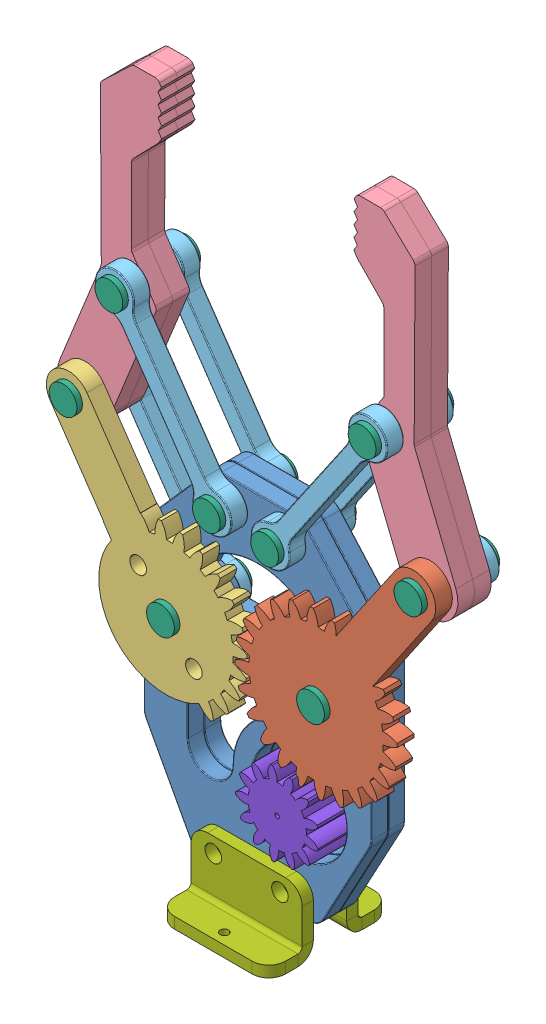
SolidWorks assembly Assem6, configuration Default. Lengths in mm.
Overall size (95 125.62 22).
25 component instances, 8 part files, 47 mates.
Components (placement in the parent):
- Part3-3-1: Part3-3 [Default] at origin size (41 62 3.03)
- part4-4-1: part4-4 [Default] at (13.5 37.5997 3) x (0 0 1) z (-0.565431 -0.824796 0) size (3 29.07 49.54)
- part5-5-1: part5-5 [Default] at (-13.5 37.5997 6) x (0 0 -1) z (0.668251 -0.743936 0) size (3 26.63 49.27)
- Part1-1-1: Part1-1 [Default] at (-31.0284 63.1684 0) x (0.375052 0.927004 0) z (0 0 1) size (60.3 20.75 3)
- Part2-2-1: Part2-2 [Default] at (-5.2398 58 4.5) x (-0.565723 0.824596 0) z (0 0 1) size (38 7 3)
- Part2-2-2: Part2-2 [Default] at (5.2398 58 4.5) x (0.565723 0.824596 0) z (0 0 1) size (38 7 3)
- Part1-1-2: Part1-1 [Default] at (31.0284 63.1684 3) x (-0.375052 0.927004 0) z (0 0 -1) size (60.3 20.75 3)
- Part3-3-2: Part3-3 [Default] at (0 0 -3) size (41 62 3.03)
- Part1-1-3: Part1-1 [Default] at (31.0284 63.1684 0) x (-0.375052 0.927004 0) z (0 0 -1) size (60.3 20.75 3)
- Part1-1-4: Part1-1 [Default] at (-31.0284 63.1684 -3) x (0.375052 0.927004 0) z (0 0 1) size (60.3 20.75 3)
- Part2-2-5: Part2-2 [Default] at (-5.2398 58 -4.5) x (-0.565723 0.824596 0) z (0 0 1) size (38 7 3)
- Part2-2-6: Part2-2 [Default] at (5.2398 58 -4.5) x (0.565723 0.824596 0) z (0 0 1) size (38 7 3)
- Part2-2-9: Part2-2 [Default] at (13.5 37.5997 -4.5) x (0.565431 0.824796 0) z (0 0 1) size (38 7 3)
- Part2-2-10: Part2-2 [Default] at (-13.5 37.5997 -4.5) x (-0.565431 0.824796 0) z (0 0 1) size (38 7 3)
- Part6-6-1: Part6-6 [Default] at (13.5 37.5997 7) x (1 0 0) z (0 1 0) size (5 14 5)
- Part7-7-1: Part7-7 [Default] at (0 -5.279 3) x (0 -1 0) z (-1 0 0) size (12 8 20)
- Part6-6-2: Part6-6 [Default] at (-13.5 37.5997 -7) x (-0.923728 -0.383049 0) z (-0.383049 0.923728 0) size (5 14 5)
- Part6-6-3: Part6-6 [Default] at (-31.0284 63.1684 -7) x (-0.923728 -0.383049 0) z (-0.383049 0.923728 0) size (5 14 5)
- Part6-6-4: Part6-6 [Default] at (-5.2398 58 -7) x (0.923728 0.383049 0) z (0.383049 -0.923728 0) size (5 14 5)
- Part6-6-5: Part6-6 [Default] at (-22.7772 83.5625 -7) x (0.923728 0.383049 0) z (0.383049 -0.923728 0) size (5 14 5)
- Part6-6-6: Part6-6 [Default] at (22.7772 83.5625 -7) x (0.923728 0.383049 0) z (0.383049 -0.923728 0) size (5 14 5)
- Part6-6-7: Part6-6 [Default] at (5.2398 58 -7) x (0.923728 0.383049 0) z (0.383049 -0.923728 0) size (5 14 5)
- Part6-6-8: Part6-6 [Default] at (31.0284 63.1684 -7) x (0.923728 0.383049 0) z (0.383049 -0.923728 0) size (5 14 5)
- Part7-7-3: Part7-7 [Default] at (0 -5.279 -3) x (0 -1 0) z (1 0 0) size (12 8 20)
- part8-8-1: part8-8 [Default] at (7.5 17.5997 7) x (0 0 -1) z (0.835413 -0.549623 0) size (13 17.5 17.5)
Mates (geometry in assembly coordinates):
- Concentric1: concentric aligned: cylinder of Part3-3-1 through (13.5 37.5997 3) axis (0 0 -1) radius 1.5; cylinder of part4-4-1 through (13.5 37.5997 53.0001) axis (0 0 -1) radius 1.5
- Coincident1: coincident anti-aligned: plane of Part3-3-1 through (0 0 3) normal (0 0 1); plane of part4-4-1 through (13.5 37.5997 3) normal (0 0 -1)
- Concentric2: concentric anti-aligned: cylinder of Part3-3-1 through (-13.5 37.5997 3) axis (0 0 -1) radius 1.5; cylinder of part5-5-1 through (-13.5 37.5997 -44.0001) axis (0 0 1) radius 1.5
- Coincident3: coincident anti-aligned: plane of Part3-3-1 through (0 0 3) normal (0 0 1); plane of part5-5-1 through (-13.5 37.5997 3) normal (0 0 -1)
- Concentric3: concentric aligned: cylinder of Part3-3-1 through (-5.2398 58 3) axis (0 0 -1) radius 1.5; cylinder of Part2-2-1 through (-5.2398 58 6) axis (0 0 -1) radius 1.5
- Coincident4: coincident anti-aligned: plane of Part3-3-1 through (0 0 3) normal (0 0 1); plane of Part2-2-1 through (-5.2398 58 3) normal (0 0 -1)
- Concentric4: concentric anti-aligned: cylinder of part5-5-1 through (-31.0284 63.1684 3) axis (0 0 1) radius 1.5; cylinder of Part1-1-1 through (-31.0284 63.1684 3) axis (0 0 -1) radius 1.5
- Concentric5: concentric aligned: cylinder of Part1-1-1 through (-22.7772 83.5625 3) axis (0 0 -1) radius 1.5; cylinder of Part2-2-1 through (-22.7772 83.5625 6) axis (0 0 -1) radius 1.5
- Concentric6: concentric anti-aligned: cylinder of part4-4-1 through (31.0284 63.1684 6) axis (0 0 -1) radius 1.5; cylinder of Part1-1-2 through (31.0284 63.1684 0) axis (0 0 1) radius 1.5
- Concentric7: concentric aligned: cylinder of Part3-3-1 through (5.2398 58 3) axis (0 0 -1) radius 1.5; cylinder of Part2-2-2 through (5.2398 58 6) axis (0 0 -1) radius 1.5
- Concentric8: concentric anti-aligned: cylinder of Part2-2-2 through (22.7772 83.5625 6) axis (0 0 -1) radius 1.5; cylinder of Part1-1-2 through (22.7772 83.5625 0) axis (0 0 1) radius 1.5
- Coincident8: coincident anti-aligned: plane of part4-4-1 through (13.5 37.5997 3) normal (0 0 -1); plane of Part1-1-2 through (31.0284 63.1684 3) normal (0 0 1)
- Coincident9: coincident anti-aligned: plane of part5-5-1 through (-13.5 37.5997 3) normal (0 0 -1); plane of Part1-1-1 through (-31.0284 63.1684 3) normal (0 0 1)
- Coincident10: coincident anti-aligned: plane of Part3-3-1 through (0 0 3) normal (0 0 1); plane of Part2-2-2 through (5.2398 58 3) normal (0 0 -1)
- Concentric11: concentric aligned: cylinder of Part3-3-2 through (13.5 37.5997 0) axis (0 0 -1) radius 1.5; cylinder of Part2-2-9 through (13.5 37.5997 -3) axis (0 0 -1) radius 1.5
- Concentric12: concentric anti-aligned: cylinder of Part1-1-3 through (31.0284 63.1684 -3) axis (0 0 1) radius 1.5; cylinder of Part2-2-9 through (31.0284 63.1684 -3) axis (0 0 -1) radius 1.5
- Coincident11: coincident anti-aligned: plane of Part3-3-2 through (0 0 -3) normal (0 0 -1); plane of Part2-2-9 through (13.5 37.5997 -3) normal (0 0 1)
- Concentric13: concentric aligned: cylinder of Part3-3-2 through (-13.5 37.5997 0) axis (0 0 -1) radius 1.5; cylinder of Part2-2-10 through (-13.5 37.5997 -3) axis (0 0 -1) radius 1.5
- Concentric14: concentric aligned: cylinder of Part1-1-4 through (-31.0284 63.1684 0) axis (0 0 -1) radius 1.5; cylinder of Part2-2-10 through (-31.0284 63.1684 -3) axis (0 0 -1) radius 1.5
- Coincident12: coincident anti-aligned: plane of Part3-3-2 through (0 0 -3) normal (0 0 -1); plane of Part2-2-10 through (-13.5 37.5997 -3) normal (0 0 1)
- Concentric15: concentric anti-aligned: cylinder of part4-4-1 through (13.5 37.5997 53.0001) axis (0 0 -1) radius 1.5; cylinder of Part6-6-1 through (13.5 37.5997 7) axis (0 0 1) radius 1.5
- Coincident15: coincident anti-aligned: plane of Part2-2-9 through (13.5 37.5997 -6) normal (0 0 -1); plane of Part6-6-1 through (11 37.5997 -6) normal (0 0 1)
- Coincident16: coincident anti-aligned: plane of Part3-3-1 through (0 0 3) normal (0 0 1); plane of Part7-7-1 through (-10 -5.279 3) normal (0 0 -1)
- Concentric16: concentric anti-aligned: cylinder of Part3-3-1 through (-6 4 3) axis (0 0 -1) radius 1.5; cylinder of Part7-7-1 through (-6 4 3) axis (0 0 1) radius 1.5
- Concentric17: concentric anti-aligned: cylinder of Part3-3-1 through (6 4 3) axis (0 0 -1) radius 1.5; cylinder of Part7-7-1 through (6 4 3) axis (0 0 1) radius 1.5
- Concentric18: concentric anti-aligned: cylinder of part5-5-1 through (-13.5 37.5997 -44.0001) axis (0 0 1) radius 1.5; cylinder of Part6-6-2 through (-13.5 37.5997 -7) axis (0 0 -1) radius 1.5
- Coincident17: coincident anti-aligned: plane of part5-5-1 through (-13.5 37.5997 6) normal (0 0 1); plane of Part6-6-2 through (-11.1907 38.5573 6) normal (0 0 -1)
- Concentric19: concentric anti-aligned: cylinder of part5-5-1 through (-31.0284 63.1684 3) axis (0 0 1) radius 1.5; cylinder of Part6-6-3 through (-31.0284 63.1684 -7) axis (0 0 -1) radius 1.5
- Coincident18: coincident anti-aligned: plane of part5-5-1 through (-13.5 37.5997 6) normal (0 0 1); plane of Part6-6-3 through (-28.719 64.126 6) normal (0 0 -1)
- Concentric20: concentric aligned: cylinder of Part2-2-1 through (-5.2398 58 6) axis (0 0 -1) radius 1.5; cylinder of Part6-6-4 through (-5.2398 58 -7) axis (0 0 -1) radius 1.5
- Coincident19: coincident anti-aligned: plane of Part2-2-1 through (-5.2398 58 6) normal (0 0 1); plane of Part6-6-4 through (-7.5491 57.0424 6) normal (0 0 -1)
- Concentric21: concentric aligned: cylinder of Part2-2-1 through (-22.7772 83.5625 6) axis (0 0 -1) radius 1.5; cylinder of Part6-6-5 through (-22.7772 83.5625 -7) axis (0 0 -1) radius 1.5
- Coincident20: coincident anti-aligned: plane of Part2-2-1 through (-5.2398 58 6) normal (0 0 1); plane of Part6-6-5 through (-25.0865 82.6048 6) normal (0 0 -1)
- Concentric22: concentric aligned: cylinder of Part2-2-2 through (22.7772 83.5625 6) axis (0 0 -1) radius 1.5; cylinder of Part6-6-6 through (22.7772 83.5625 -7) axis (0 0 -1) radius 1.5
- Coincident21: coincident anti-aligned: plane of Part2-2-2 through (5.2398 58 6) normal (0 0 1); plane of Part6-6-6 through (20.4679 82.6048 6) normal (0 0 -1)
- Concentric23: concentric aligned: cylinder of Part2-2-2 through (5.2398 58 6) axis (0 0 -1) radius 1.5; cylinder of Part6-6-7 through (5.2398 58 -7) axis (0 0 -1) radius 1.5
- Coincident22: coincident anti-aligned: plane of Part2-2-2 through (5.2398 58 6) normal (0 0 1); plane of Part6-6-7 through (2.9305 57.0424 6) normal (0 0 -1)
- Concentric24: concentric aligned: cylinder of part4-4-1 through (31.0284 63.1684 6) axis (0 0 -1) radius 1.5; cylinder of Part6-6-8 through (31.0284 63.1684 -7) axis (0 0 -1) radius 1.5
- Coincident23: coincident anti-aligned: plane of part4-4-1 through (13.5 37.5997 6) normal (0 0 1); plane of Part6-6-8 through (28.719 62.2108 6) normal (0 0 -1)
- Coincident25: coincident anti-aligned: plane of Part3-3-2 through (0 0 -3) normal (0 0 -1); plane of Part7-7-3 through (10 -5.279 -3) normal (0 0 1)
- Concentric27: concentric aligned: cylinder of Part3-3-2 through (6 4 0) axis (0 0 -1) radius 1.5; cylinder of Part7-7-3 through (6 4 -3) axis (0 0 -1) radius 1.5
- Concentric28: concentric aligned: cylinder of Part3-3-2 through (-6 4 0) axis (0 0 -1) radius 1.5; cylinder of Part7-7-3 through (-6 4 -3) axis (0 0 -1) radius 1.5
- Concentric29: concentric anti-aligned: cylinder of Part3-3-1 through (7.5 17.5997 3) axis (0 0 -1) radius 8.5; cylinder of part8-8-1 through (7.5 17.5997 -6) axis (0 0 1) radius 8.75
- Coincident26: coincident anti-aligned: plane of Part3-3-2 through (0 0 -3) normal (0 0 -1); plane of part8-8-1 through (7.5 17.5997 -3) normal (0 0 1)
- LimitAngle1: limit planar angle = 2.540637 rad anti-aligned: plane of part5-5-1 through (-16.7992 35.338 3) normal (-0.824796 -0.565431 0); plane of Part3-3-1 through (-20.5 47.8997 3) normal (-1 0 0)
- GearMate1: gear = 1 : 1 mm: cylinder of part5-5-1 through (-13.5 37.5997 3) axis (0 0 1) radius 12.0927; cylinder of part4-4-1 through (13.5 37.5997 6) axis (0 0 -1) radius 12.0927
- GearMate2: gear = 13 : 24 mm: cylinder of part8-8-1 through (7.5 17.5997 -3) axis (0 0 1) radius 5.249; cylinder of part4-4-1 through (13.5 37.5997 6) axis (0 0 -1) radius 12.0927
